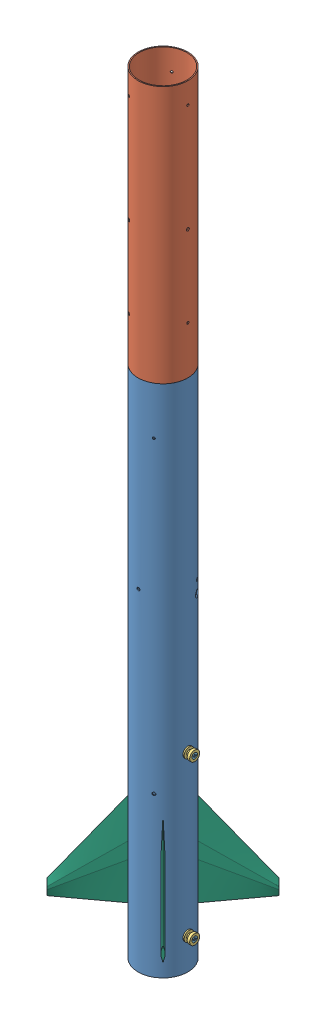
SolidWorks assembly S1A_Airframe, configuration Default. Lengths in mm.
Overall size (189.08 1234.01 189.08).
14 component instances, 6 part files, 15 mates.
Components (placement in the parent):
- S1A_Aft_Body_Tube-2: S1A_Aft_Body_Tube [Default] at origin size (79.58 822.53 79.58)
- S1A_Forward_Body_Tube-1: S1A_Forward_Body_Tube [Default] at (0 822.5282 0) size (79.58 411.48 79.58)
- S1A_Railguide-1: S1A_Railguide [Default] at (39.7891 50.8 0) size (19.05 19 19)
  - S1A_Railguide_Bolt-1: S1A_Railguide_Bolt [Default] at origin size (10.92 16 16)
  - S1A_Welded_Nut_Railguide-1: S1A_Welded_Nut_Railguide [Default] at (-2.6264 0 0) x (0 0 1) z (-1 0 0) size (19 19 11)
  - S1A_10-32_Flathead_RailguideScrew-2: S1A_10-32_Flathead_RailguideScrew [91099A365] at (1.397 0 0) x (-1 0 0) z (0 0 -1) size (19.05 8.95 8.95)
- S1A_Railguide-2: S1A_Railguide [Default] at (39.7891 304.8 0) size (19.05 19 19)
  - S1A_Railguide_Bolt-1: S1A_Railguide_Bolt [Default] at origin size (10.92 16 16)
  - S1A_Welded_Nut_Railguide-1: S1A_Welded_Nut_Railguide [Default] at (-2.6264 0 0) x (0 0 1) z (-1 0 0) size (19 19 11)
  - S1A_10-32_Flathead_RailguideScrew-2: S1A_10-32_Flathead_RailguideScrew [91099A365] at (1.397 0 0) x (-1 0 0) z (0 0 -1) size (19.05 8.95 8.95)
- S1A_Fin_Representation-1: S1A_Fin_Representation [Default] at (28.1351 150.368 28.1351) x (0.707107 0 0.707107) z (-0.707107 0 0.707107) size (91.39 148.58 5.04)
- S1A_Fin_Representation-5: S1A_Fin_Representation [Default] at (-28.1351 150.368 28.1351) x (-0.707107 0 0.707107) z (-0.707107 0 -0.707107) size (91.39 148.58 5.04)
- S1A_Fin_Representation-6: S1A_Fin_Representation [Default] at (-28.1351 150.368 -28.1351) x (-0.707107 0 -0.707107) z (0.707107 0 -0.707107) size (91.39 148.58 5.04)
- S1A_Fin_Representation-7: S1A_Fin_Representation [Default] at (28.1351 150.368 -28.1351) x (0.707107 0 -0.707107) z (0.707107 0 0.707107) size (91.39 148.58 5.04)
Mates (geometry in assembly coordinates):
- Coincident1: coincident anti-aligned: line of S1A_Aft_Body_Tube-2 through (894.08 0 -40.64) axis (0 0 1)
- Coincident2: coincident aligned: plane of S1A_Aft_Body_Tube-2 through (0 0 0) normal (0 1 0)
- Parallel1: parallel aligned: plane of S1A_Aft_Body_Tube-2 through (0 0 0) normal (0 0 1)
- Coincident3: coincident anti-aligned: line of S1A_Forward_Body_Tube-1 through (167.64 0 814.9082) axis (0 0 1)
- Coincident4: coincident aligned: plane of S1A_Aft_Body_Tube-2 through (0 822.5282 0) normal (0 1 0); plane of S1A_Forward_Body_Tube-1 through (0 822.5282 0) normal (0 1 0)
- Parallel2: parallel aligned: plane of S1A_Forward_Body_Tube-1 through (0 822.5282 0) normal (0 0 1)
- Concentric1: concentric anti-aligned: cylinder of S1A_Aft_Body_Tube-2 through (-39.7901 304.8 0) axis (1 0 0) radius 3.175; cylinder of S1A_Railguide-2/S1A_Welded_Nut_Railguide-1 through (48.1635 304.8 0) axis (-1 0 0) radius 3.1979
- Tangent2: tangent aligned: cylinder of S1A_Aft_Body_Tube-2 through (0 822.5282 0) axis (0 -1 0) radius 38.1635; plane of S1A_Railguide-2/S1A_Welded_Nut_Railguide-1 through (38.1635 304.8 0) normal (1 0 0)
- Coincident5: coincident aligned: plane of S1A_Railguide-1/S1A_Welded_Nut_Railguide-1 through (38.1635 50.8 0) normal (1 0 0); plane of S1A_Railguide-2/S1A_Welded_Nut_Railguide-1 through (38.1635 304.8 0) normal (1 0 0)
- Concentric2: concentric anti-aligned: cylinder of S1A_Aft_Body_Tube-2 through (-39.7901 50.8 0) axis (1 0 0) radius 3.175; cylinder of S1A_Railguide-1/S1A_Welded_Nut_Railguide-1 through (48.1635 50.8 0) axis (-1 0 0) radius 3.1979
- Parallel3: parallel aligned: plane of S1A_Railguide-1 through (39.7891 50.8 0) normal (0 1 0)
- Parallel4: parallel aligned: plane of S1A_Railguide-2 through (39.7891 304.8 0) normal (0 1 0)
- Distance2: distance = 150.368 mm: plane of assembly through (0 0 0) normal (0 1 0); plane of assembly; plane of S1A_Fin_Representation-1 through (28.1351 150.368 28.1351) normal (0 1 0)
- Distance3: distance = 0 mm: plane of assembly through (0 0 0) normal (0.707107 0 -0.707107); plane of assembly; plane of S1A_Fin_Representation-1 through (28.1351 150.368 28.1351) normal (-0.707107 0 0.707107)
- Coincident6: coincident: plane of assembly through (28.1351 0 28.1351) normal (0.707107 0 0.707107); plane of S1A_Fin_Representation-1 through (28.1351 150.368 28.1351) normal (0.707107 0 0.707107); plane of assembly
